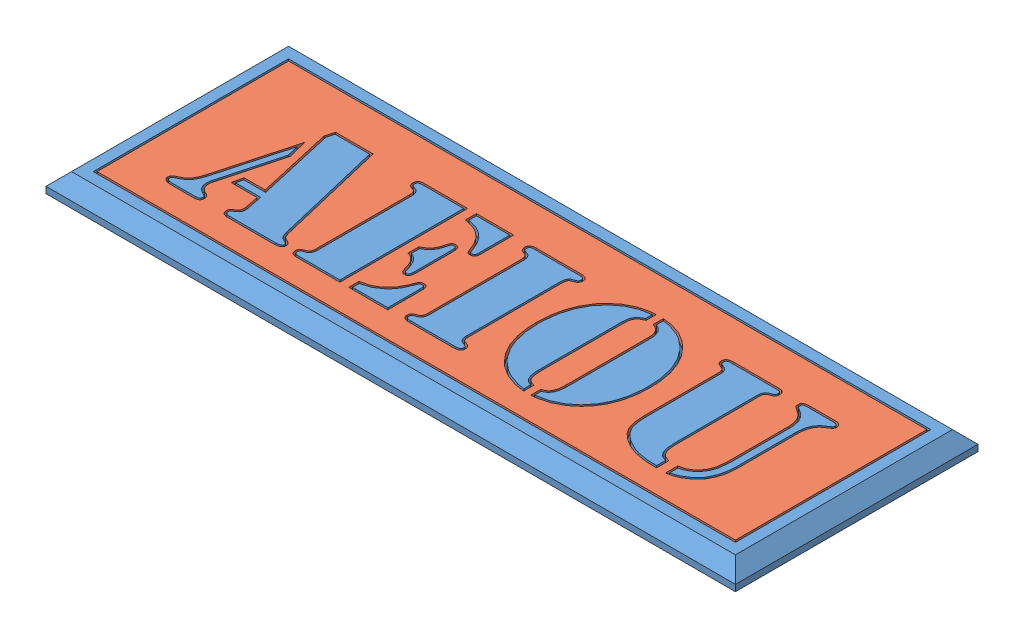
SolidWorks assembly test_text_assy, configuration Default. Lengths in mm.
Overall size (54 1.5 19).
2 component instances, 2 part files, 3 mates.
Components (placement in the parent):
- test_text_base-1: test_text_base [Default] at origin size (54 1.5 19)
- test_text_overlay-1: test_text_overlay [Default] at (0 1 0) size (50 0.5 15)
Mates (geometry in assembly coordinates):
- Coincident1: coincident aligned: plane of test_text_overlay-1 through (0 1 0) normal (0 0 1); plane of assembly through (0 0 0) normal (0 0 1)
- Coincident2: coincident aligned: plane of test_text_overlay-1 through (0 1 0) normal (1 0 0); plane of assembly through (0 0 0) normal (1 0 0)
- Coincident5: coincident aligned: plane of test_text_base-1 through (0 1.5 0) normal (0 1 0); plane of test_text_overlay-1 through (0 1.5 0) normal (0 1 0)
